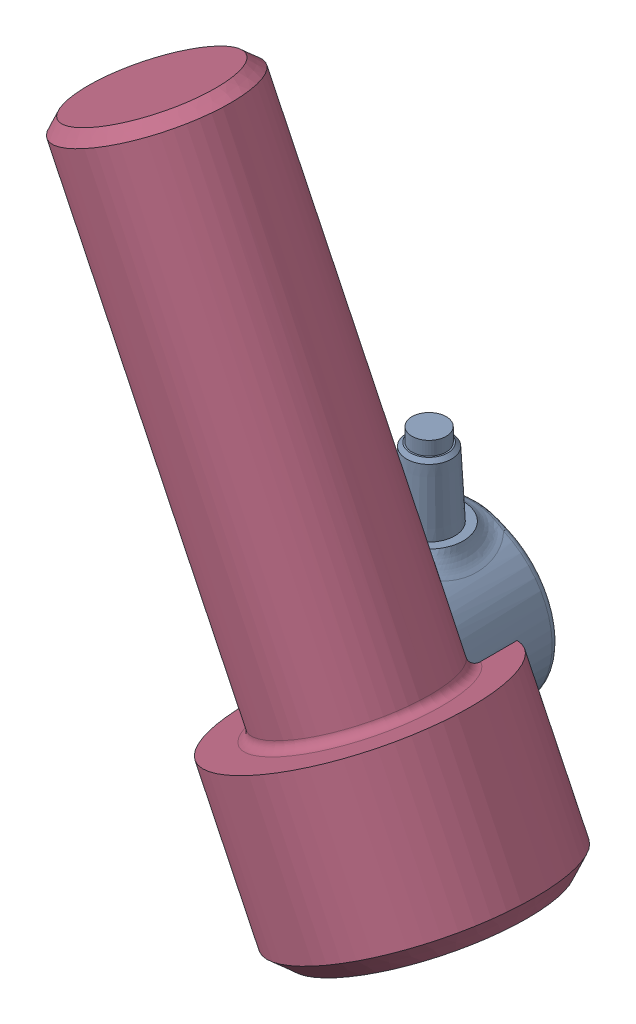
SolidWorks assembly Codeur_2MRH, configuration Default. Lengths in mm.
Overall size (73.28 100.3 40.25).
8 component instances, 6 part files, 16 mates.
Components (placement in the parent):
- corps_codeur_2MRH-1: corps_codeur_2MRH [Default] at (3.2886 -2.5929 -14.3048) size (24 36.75 20.04)
- mandrin_codeur_2MRH-1: mandrin_codeur_2MRH [Default] at (3.2886 -2.5929 -3.8048) x (-0.434638 0.900605 0) z (0 0 1) size (6 6 14)
- bague_codeur_2MRH-1: bague_codeur_2MRH [Default] at (3.2886 -2.5929 5.6952) x (0.434638 -0.900605 0) z (0 0 1) size (13.5 13.48 4.5)
- Socket Head Cap Screw_AM-1: Socket Head Cap Screw_AM [PreviewCfg] at (18.8425 -24.5111 7.9452) x (-0.434638 0.900605 0) z (0 0 1) size (94 36 36)
- Vis_fendue_tete_bombee_M2_L5-1: Vis_fendue_tete_bombee_M2_L5 [B18.6.7M - M2 x 0.4 x 4 Slotted PHMS --4N] at (10.6498 1.6571 7.2952) x (0 0 -1) z (0.728333 -0.685223 0) size (5.65 4 4)
- Vis_fendue_tete_bombee_M2_L5-2: Vis_fendue_tete_bombee_M2_L5 [B18.6.7M - M2 x 0.4 x 4 Slotted PHMS --4N] at (-4.0726 1.6571 7.2952) x (0 0 -1) z (0.998972 -0.045336 0) size (5.65 4 4)
- Vis_fendue_tete_bombee_M2_L5-3: Vis_fendue_tete_bombee_M2_L5 [B18.6.7M - M2 x 0.4 x 4 Slotted PHMS --4N] at (3.2886 -11.0929 7.2952) x (0 0 -1) z (-0.043781 0.999041 0) size (5.65 4 4)
- Bride_membrane-1: Bride_membrane [Default] at (3.2886 -2.5929 5.6952) x (0.5 0.866025 0) z (-0.866025 0.5 0) size (28.11 0.5 27.75)
Mates (geometry in assembly coordinates):
- Coaxiale2: concentric anti-aligned: cylinder of corps_codeur_2MRH-1 through (3.2886 -2.5929 -3.8048) axis (0 0 1) radius 3; cylinder of mandrin_codeur_2MRH-1 through (3.2886 -2.5929 10.1952) axis (0 0 -1) radius 3
- Coïncidente1: coincident anti-aligned: plane of corps_codeur_2MRH-1 through (3.2886 -2.5929 -3.8048) normal (0 0 1); plane of mandrin_codeur_2MRH-1 through (3.2886 -2.5929 -3.8048) normal (0 0 -1)
- Coïncidente2: coincident anti-aligned: plane of corps_codeur_2MRH-1 through (3.2886 -2.5929 5.6952) normal (0 0 1); plane of bague_codeur_2MRH-1 through (3.2886 -2.5929 5.6952) normal (0 0 -1)
- Coaxiale3: concentric aligned: cylinder of mandrin_codeur_2MRH-1 through (3.2886 -2.5929 10.1952) axis (0 0 -1) radius 3; cylinder of bague_codeur_2MRH-1 through (3.2886 -2.5929 10.1952) axis (0 0 -1) radius 3
- Parallèle1: parallel aligned: plane of mandrin_codeur_2MRH-1 through (3.4051 -2.2591 0.1952) normal (0.434638 -0.900605 0); plane of bague_codeur_2MRH-1 through (9.1337 0.7831 5.6942) normal (0.434638 -0.900605 0)
- Coaxiale41: concentric anti-aligned: cylinder of bague_codeur_2MRH-1 through (8.4112 -2.8966 7.9452) axis (-0.434638 0.900605 0) radius 0.75; cylinder of Socket Head Cap Screw_AM-1 through (32.6423 -53.1053 7.9452) axis (0.434638 -0.900605 0) radius 18
- Coïncidente41: coincident anti-aligned: plane of bague_codeur_2MRH-1 through (8.4112 -2.8966 7.9452) normal (0.434638 -0.900605 0); plane of Socket Head Cap Screw_AM-1 through (-7.7997 -10.7201 7.9452) normal (-0.434638 0.900605 0)
- Coaxiale81: concentric aligned: cylinder of corps_codeur_2MRH-1 through (10.6498 1.6571 5.1952) axis (0 0 1) radius 0.8; cylinder of Vis_fendue_tete_bombee_M2_L5-1 through (10.6498 1.6571 32.6952) axis (0 0 1) radius 2
- Coaxiale91: concentric aligned: cylinder of corps_codeur_2MRH-1 through (-4.0726 1.6571 5.1952) axis (0 0 1) radius 0.8; cylinder of Vis_fendue_tete_bombee_M2_L5-2 through (-4.0726 1.6571 32.6952) axis (0 0 1) radius 2
- Coaxiale101: concentric aligned: cylinder of corps_codeur_2MRH-1 through (3.2886 -11.0929 5.1952) axis (0 0 1) radius 0.8; cylinder of Vis_fendue_tete_bombee_M2_L5-3 through (3.2886 -11.0929 32.6952) axis (0 0 1) radius 2
- Coïncidente102: coincident anti-aligned: plane of corps_codeur_2MRH-1 through (3.2886 -2.5929 5.1952) normal (0 0 1); plane of Bride_membrane-1 through (3.2886 -2.5929 5.1952) normal (0 0 -1)
- Coïncidente103: coincident aligned: circle of corps_codeur_2MRH-1; cylinder of Bride_membrane-1 through (3.2886 -2.5929 5.1952) axis (0 0 1) radius 7.75
- Coaxiale102: concentric aligned: cylinder of corps_codeur_2MRH-1 through (-4.0726 1.6571 5.1952) axis (0 0 1) radius 0.8; cylinder of Bride_membrane-1 through (-4.0726 1.6571 5.1952) axis (0 0 1) radius 1.5
- Coïncidente104: coincident anti-aligned: plane of Vis_fendue_tete_bombee_M2_L5-2 through (-4.0273 2.6561 5.6952) normal (0 0 -1); plane of Bride_membrane-1 through (3.2886 -2.5929 5.6952) normal (0 0 1)
- Coïncidente105: coincident anti-aligned: plane of Vis_fendue_tete_bombee_M2_L5-1 through (11.335 2.3854 5.6952) normal (0 0 -1); plane of Bride_membrane-1 through (3.2886 -2.5929 5.6952) normal (0 0 1)
- Coïncidente106: coincident anti-aligned: plane of Vis_fendue_tete_bombee_M2_L5-3 through (2.2896 -11.1367 5.6952) normal (0 0 -1); plane of Bride_membrane-1 through (3.2886 -2.5929 5.6952) normal (0 0 1)
